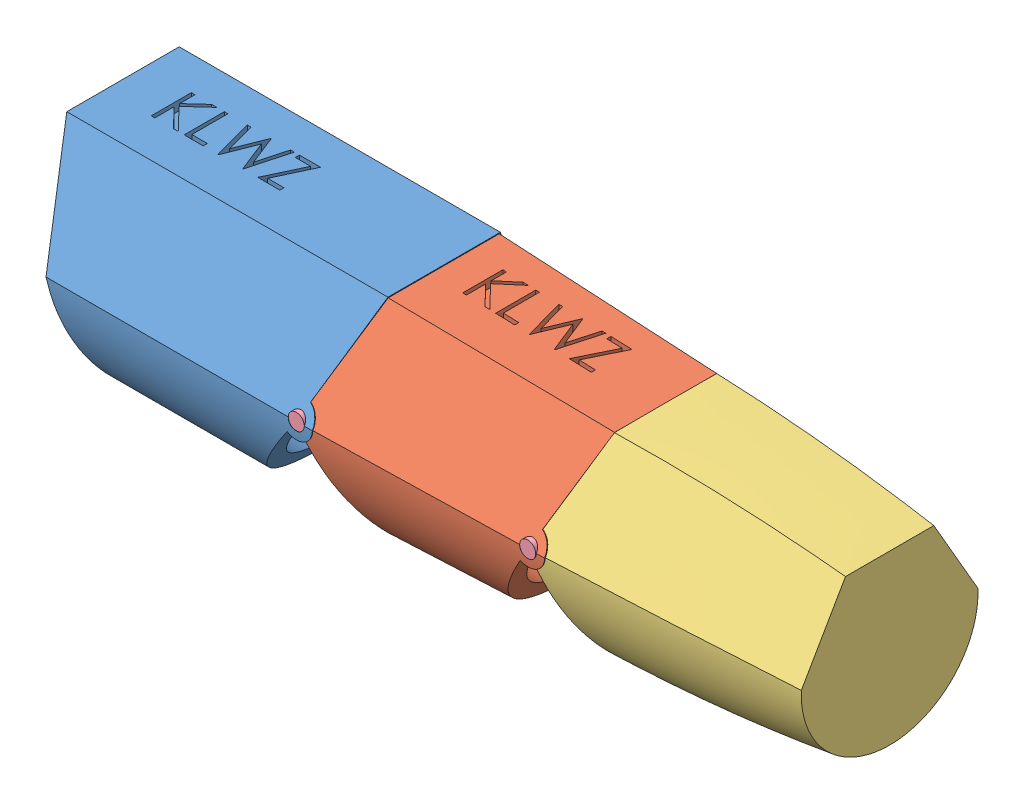
SolidWorks assembly Pinky Finger-KLWZ, configuration Default. Lengths in mm.
Overall size (60.63 17.12 17.87).
11 component instances, 6 part files, 16 mates.
Components (placement in the parent):
- Pinky Bottom-KLWZ-1: Pinky Bottom-KLWZ [Default] at (-10.9157 20.3951 24.52) size (25.4 17.11 17.82)
- Pinky Middle-KLWZ-1: Pinky Middle-KLWZ [Default] at (11.6821 20.3951 24.52) size (21.59 16.79 17.87)
- Pinky Tip-KLWZ-1: Pinky Tip-KLWZ [Default] at (29.3929 19.6656 24.52) size (21.6 16.32 16.67)
- Hinge Pin-KLWZ-1: Hinge Pin-KLWZ [Default] at (11.6821 12.6961 31.886) x (1 0 0) z (0 -1 0) size (1.27 1.52 1.27)
- Hinge Pin-KLWZ-2: Hinge Pin-KLWZ [Default] at (29.3929 12.5166 31.2975) x (1 0 0) z (0 -1 0) size (1.27 1.52 1.27)
- Hinge Pin-KLWZ-3: Hinge Pin-KLWZ [Default] at (11.6821 12.6961 15.63) x (1 0 0) z (0 -1 0) size (1.27 1.52 1.27)
- Hinge Pin-KLWZ-4: Hinge Pin-KLWZ [Default] at (29.3929 12.5166 16.2186) x (1 0 0) z (0 -1 0) size (1.27 1.52 1.27)
- Hinge 3-KLWZ-1: Hinge 3-KLWZ [Default] at (-6.8084 1.7278 21.9846) x (0.998734 -0.050311 0) z (0 0 1) size (2.55 0.58 2.54) (flexible)
  - Hinge 3-KLWZ-1: Hinge 3-KLWZ [Default] at (1.5197 1.8887 1.2654) size (1.52 0.51 2.54)
  - Hinge 3-KLWZ-2: Hinge 3-KLWZ [Default] at (1.5197 1.8887 3.8054) x (-0.998734 -0.050311 0) z (0 0 -1) size (1.52 0.51 2.54)
  - Hinge 3 Pin-KLWZ-1: Hinge 3 Pin-KLWZ [Default] at (1.5197 1.8887 3.8054) x (1 0 0) z (0 1 0) size (0.25 2.54 0.25)
Mates (geometry in assembly coordinates):
- Coincident1: coincident aligned: circle of Pinky Bottom-KLWZ-1; circle of Pinky Middle-KLWZ-1
- Coincident2: coincident anti-aligned: circle of Pinky Bottom-KLWZ-1; circle of Pinky Middle-KLWZ-1
- Coincident3: coincident aligned: circle of Pinky Middle-KLWZ-1; circle of Pinky Tip-KLWZ-1
- Coincident4: coincident anti-aligned: circle of Pinky Middle-KLWZ-1; circle of Pinky Tip-KLWZ-1
- Concentric1: concentric anti-aligned: cylinder of Pinky Bottom-KLWZ-1 through (11.6821 12.6961 15.6155) axis (0 0 1) radius 0.635; cylinder of Hinge Pin-KLWZ-1 through (11.6821 12.6961 33.41) axis (0 0 -1) radius 0.635
- Concentric2: concentric anti-aligned: cylinder of Pinky Middle-KLWZ-1 through (29.3929 12.5166 15.6155) axis (0 0 1) radius 0.635; cylinder of Hinge Pin-KLWZ-2 through (29.3929 12.5166 32.8215) axis (0 0 -1) radius 0.635
- Coincident5: coincident: point of Pinky Bottom-KLWZ-1; circle of Hinge Pin-KLWZ-1
- Coincident6: coincident: point of Pinky Middle-KLWZ-1; circle of Hinge Pin-KLWZ-2
- Concentric3: concentric anti-aligned: cylinder of Pinky Bottom-KLWZ-1 through (11.6821 12.6961 15.6155) axis (0 0 1) radius 0.635; cylinder of Hinge Pin-KLWZ-3 through (11.6821 12.6961 17.154) axis (0 0 -1) radius 0.635
- Concentric4: concentric anti-aligned: cylinder of Pinky Middle-KLWZ-1 through (29.3929 12.5166 15.6155) axis (0 0 1) radius 0.635; cylinder of Hinge Pin-KLWZ-4 through (29.3929 12.5166 17.7426) axis (0 0 -1) radius 0.635
- Coincident7: coincident: point of Pinky Middle-KLWZ-1; circle of Hinge Pin-KLWZ-4
- Coincident8: coincident: point of Pinky Bottom-KLWZ-1; circle of Hinge Pin-KLWZ-3
- LimitAngle1: limit planar angle = 0 rad anti-aligned: plane of Pinky Bottom-KLWZ-1 through (14.4843 20.3951 15.6155) normal (0.939693 -0.34202 0); plane of Pinky Middle-KLWZ-1 through (15.244 22.4824 15.6155) normal (-0.939693 0.34202 0)
- LimitAngle2: limit planar angle = 0 rad anti-aligned: plane of Pinky Middle-KLWZ-1 through (32.0021 19.6855 15.6155) normal (0.939693 -0.34202 0); plane of Pinky Tip-KLWZ-1 through (33.1355 22.7993 16.195) normal (-0.939693 0.34202 0)
- Coincident9: coincident anti-aligned: line of Pinky Bottom-KLWZ-1 through (-3.9256 3.7916 25.79) axis (0 0 -1); line of Hinge 3-KLWZ-1/Hinge 3-KLWZ-2 through (-3.9256 3.7916 23.25) axis (0 0 1)
- Coincident10: coincident aligned: line of Pinky Bottom-KLWZ-1 through (-4.8725 3.7916 25.79) axis (1 0 0); line of Hinge 3-KLWZ-1/Hinge 3-KLWZ-2 through (-4.9416 3.7916 25.79) axis (1 0 0)
